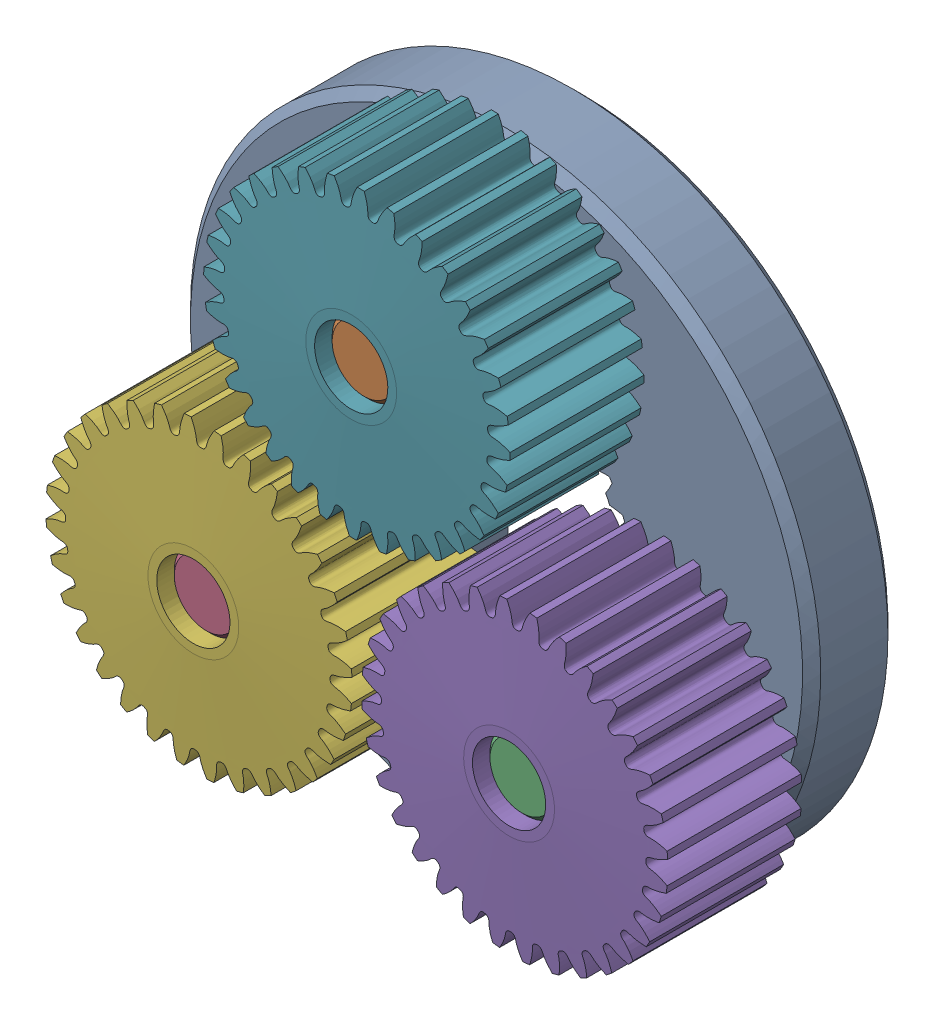
SolidWorks assembly 217-2625-100, configuration Default. Lengths in mm.
Overall size (39.26 38.9 12.7).
7 component instances, 3 part files, 0 mates.
Components (placement in the parent):
- 217-2625-008 Rev1-1: 217-2625-008 Rev1 [Default] at origin size (34.7 34.7 4.7)
- 217-2625-010 Rev1-1: 217-2625-010 Rev1 [Default] at (0 10.193 3.65) x (0.999813 0.019336 0) z (0 0 1) size (4 4 12)
- 217-2625-010 Rev1-2: 217-2625-010 Rev1 [Default] at (8.691 -5.3258 3.65) size (4 4 12)
- 217-2625-010 Rev1-3: 217-2625-010 Rev1 [Default] at (-8.691 -5.3258 3.65) size (4 4 12)
- 217-2625-005 Rev1_Planet_Revolving_Follower01-1: 217-2625-005 Rev1_Planet_Revolving_Follower01 [Default] at (8.691 -5.3258 6.35) x (0.932816 0.360354 0) z (0 0 1) size (16.91 16.92 8)
- 217-2625-005 Rev1_Planet_Revolving_Follower01-2: 217-2625-005 Rev1_Planet_Revolving_Follower01 [Default] at (-8.691 -5.3258 6.35) x (-0.932788 -0.360426 0) z (0 0 1) size (16.91 16.92 8)
- 217-2625-005 Rev1_Planet_Revolving_Follower01-3: 217-2625-005 Rev1_Planet_Revolving_Follower01 [Default] at (0 10.193 6.35) x (0.893583 0.448898 0) z (0 0 1) size (16.91 16.92 8)
